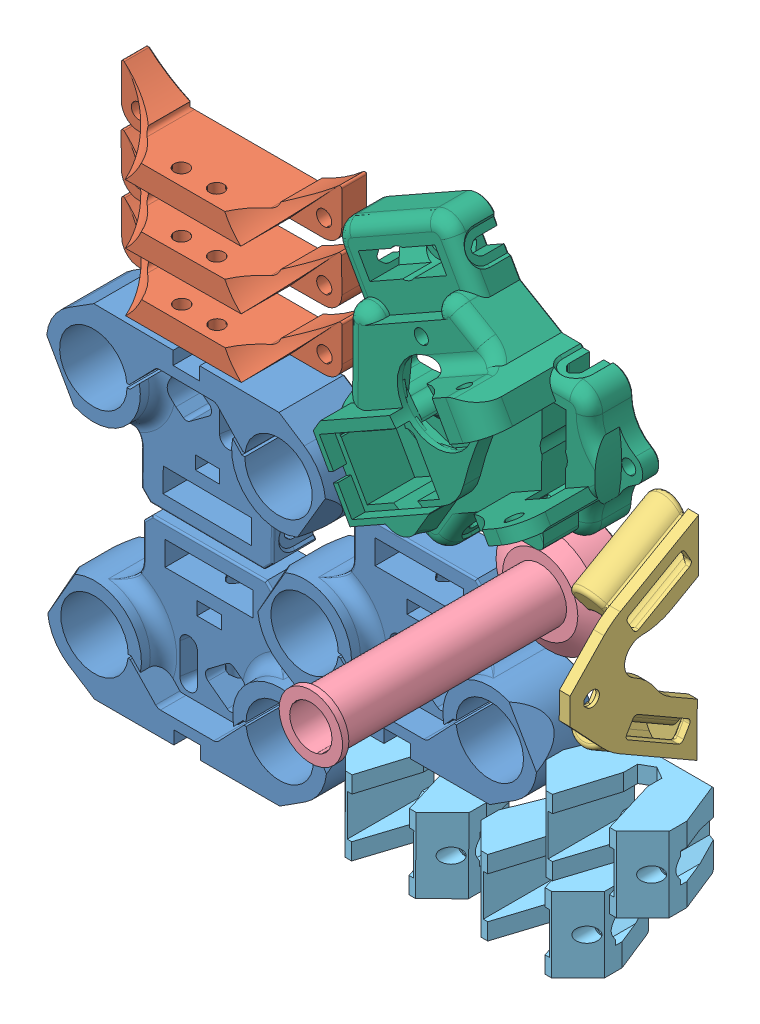
SolidWorks assembly 1312a, configuration Default. Lengths in mm.
Overall size (200 200 62.13).
12 component instances, 6 part files, 9 mates.
Components (placement in the parent):
- 1304-1: 1304 [Default] at (0.42 -14.2896 0) size (63.3 37.65 15)
- 1304-2: 1304 [Default] at (-47.4844 13.7182 0) x (-0.999962 0.008727 0) z (0 0 1) size (63.3 37.65 15)
- 1304-3: 1304 [Default] at (-47.2282 -38.4163 0) size (63.3 37.65 15)
- 1245-1: 1245 [Default] at (-46.1516 65.9989 0) size (50 13 17)
- 1245-2: 1245 [Default] at (-46.0559 39.2764 0) size (50 13 17)
- 1245-3: 1245 [Default] at (-46.1688 52.6252 0) x (0.999962 0.008727 0) z (0 0 1) size (50 13 17)
- 1247-1: 1247 [Default] at (53.5888 14.4323 1) x (-0.008727 -0.999962 0) z (-0.999962 0.008727 0) size (51.6 29.13 11.32)
- 1249-1: 1249 [Default] at (27.8392 15.0581 0) x (0 0 -1) z (1 0 0) size (62 24 24)
- 1243-4: 1243 [Default] at (18.4446 -48.9814 0) size (28 17 20)
- 1243-5: 1243 [Default] at (33.1139 -29.8244 0) size (28 17 20)
- 1243-6: 1243 [Default] at (-12.4369 -48.6305 0) x (0.999962 -0.008727 0) z (0 0 1) size (28 17 20)
- 1301-1: 1301 [Default] at (7.9279 44.4496 0) x (0.870356 0.492424 0) z (0 0 1) size (65.4 57.84 25.8)
Mates (geometry in assembly coordinates):
- Coincident1: coincident aligned: plane of 1304-1 through (-20.58 -14.2896 0) normal (0 0 -1); plane of 1243-4 through (18.4446 -48.9814 0) normal (0 0 -1)
- Coincident2: coincident aligned: plane of 1304-1 through (-20.58 -14.2896 0) normal (0 0 -1); plane of 1243-5 through (33.1139 -29.8244 0) normal (0 0 -1)
- Coincident3: coincident aligned: plane of 1304-1 through (-20.58 -14.2896 0) normal (0 0 -1); plane of 1243-6 through (-12.4369 -48.6305 0) normal (0 0 -1)
- Coincident4: coincident aligned: plane of 1304-1 through (-19.1089 -13.1976 0) normal (0 0 -1); plane of ? through (-23.6603 63.634 0) normal (0 0 -1)
- Coincident5: coincident aligned: plane of 1304-1 through (-19.1089 -13.1976 0) normal (0 0 -1); plane of ? through (54.3898 -38.9158 0) normal (0 0 -1)
- Coincident6: coincident aligned: plane of 1304-1 through (-19.1089 -13.1976 0) normal (0 0 -1); plane of ? through (53.0996 -2.5306 0) normal (0 0 -1)
- Coincident7: coincident aligned: plane of 1304-1 through (-20.58 -14.2896 0) normal (0 0 -1); plane of 1301-1 through (4.0174 72.6844 0) normal (0 0 -1)
- Coincident8: coincident aligned: plane of 1247-1 through (38.6766 24.5628 0) normal (0 0 -1); plane of 1301-1 through (4.0174 72.6844 0) normal (0 0 -1)
- Coincident9: coincident aligned: plane of 1249-1 through (15.8392 15.0581 0) normal (0 0 -1); plane of 1301-1 through (4.0174 72.6844 0) normal (0 0 -1)
